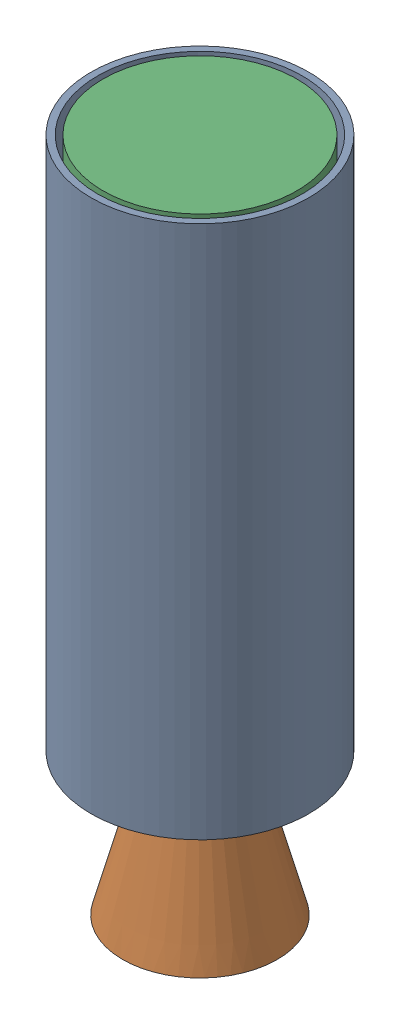
SolidWorks assembly Motor_Assembly_Test#1, configuration Default. Lengths in mm.
Overall size (124.22 310.2 124.22).
3 component instances, 3 part files, 4 mates.
Components (placement in the parent):
- Casing_Test#1-1: Casing_Test#1 [Default] at (90.6963 -357.5404 195.0485) size (100 245 100)
- Nozzle2-1: Nozzle2 [Default] at (90.6963 -433.9404 195.0485) x (0 -1 0) z (-0.811608 0 -0.584202) size (115.2 88.99 88.99)
- Bulkhead-1: Bulkhead [Default] at (90.6963 -112.5404 195.0485) x (0 -1 0) z (0.82025 0 -0.572005) size (50 89 89)
Mates (geometry in assembly coordinates):
- Concentric1: concentric aligned: cylinder of Casing_Test#1-1 through (90.6963 -112.5404 195.0485) axis (0 -1 0) radius 47; cylinder of Nozzle2-1 through (90.6963 -433.9404 195.0485) axis (0 -1 0) radius 44.4963
- Coincident1: coincident aligned: plane of Casing_Test#1-1 through (90.6963 -357.5404 195.0485) normal (0 -1 0); plane of Nozzle2-1 through (64.7014 -357.5404 231.1621) normal (0 -1 0)
- Concentric2: concentric anti-aligned: cylinder of Casing_Test#1-1 through (90.6963 -112.5404 195.0485) axis (0 -1 0) radius 47; cylinder of Bulkhead-1 through (90.6963 -112.5404 195.0485) axis (0 1 0) radius 44.5
- Coincident2: coincident aligned: plane of Casing_Test#1-1 through (90.6963 -112.5404 195.0485) normal (0 1 0); plane of Bulkhead-1 through (90.6963 -112.5404 195.0485) normal (0 1 0)
